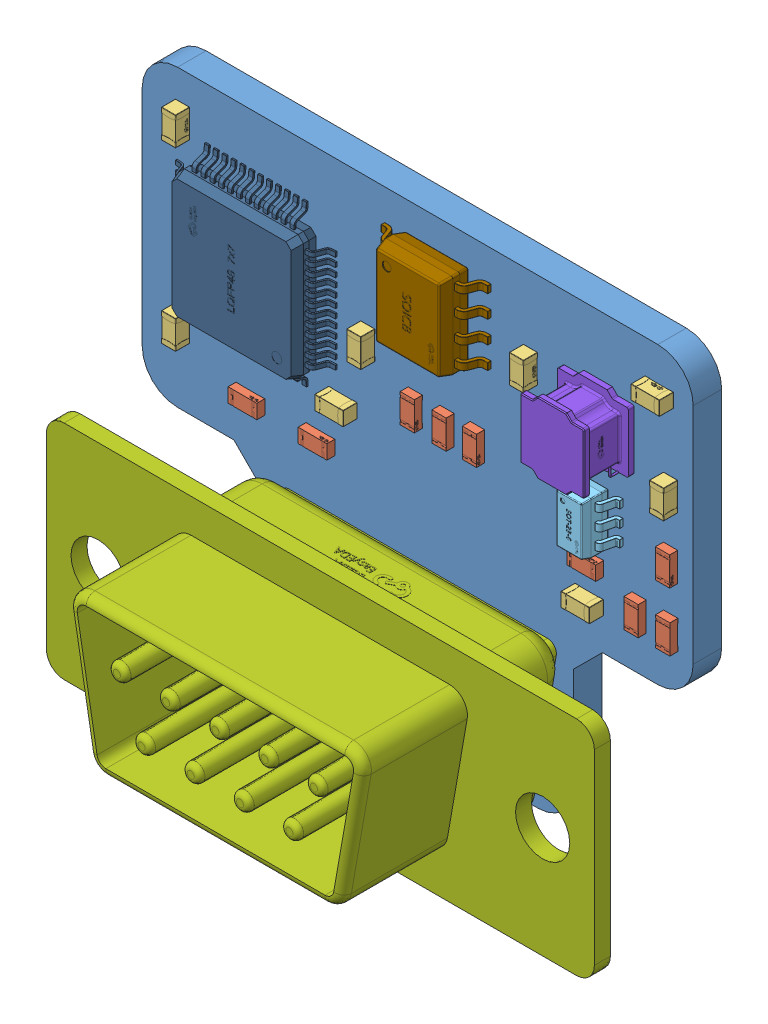
SolidWorks assembly ModbusRTU, configuration 默认. Lengths in mm.
Overall size (30.97 27.51 15.91).
109 component instances, 10 part files, 0 mates.
Components (placement in the parent):
- COMPOUND-1: COMPOUND [默认] at origin size (30.97 25.95 1.6)
- R4-1: R4 [默认] at (94.7422 -30.9881 1.6001) x (0 1 0) z (0 0 1) size (1.62 0.82 0.45)
  - R0603-1: R0603 [默认] at origin size (1.62 0.82 0.45)
    - COMPOUND_2-1: COMPOUND_2 [默认] at origin size (1.62 0.82 0.45)
- R5-1: R5 [默认] at (96.5202 -30.9881 1.6001) x (0 -1 0) z (0 0 1) size (1.62 0.82 0.45)
  - R0603-1: R0603 [默认] at origin size (1.62 0.82 0.45)
    - COMPOUND_2-1: COMPOUND_2 [默认] at origin size (1.62 0.82 0.45)
- R13-1: R13 [默认] at (97.0282 -34.0361 0) x (1 0 0) z (0 0 -1) size (1.62 0.82 0.45)
  - R0603-1: R0603 [默认] at origin size (1.62 0.82 0.45)
    - COMPOUND_2-1: COMPOUND_2 [默认] at origin size (1.62 0.82 0.45)
- R14-1: R14 [默认] at (93.9802 -36.8301 0) x (1 0 0) z (0 0 -1) size (1.62 0.82 0.45)
  - R0603-1: R0603 [默认] at origin size (1.62 0.82 0.45)
    - COMPOUND_2-1: COMPOUND_2 [默认] at origin size (1.62 0.82 0.45)
- R22-1: R22 [默认] at (93.9802 -34.0361 0) x (-1 0 0) z (0 0 -1) size (1.62 0.82 0.45)
  - R0603-1: R0603 [默认] at origin size (1.62 0.82 0.45)
    - COMPOUND_2-1: COMPOUND_2 [默认] at origin size (1.62 0.82 0.45)
- R23-1: R23 [默认] at (93.9802 -35.4331 0) x (1 0 0) z (0 0 -1) size (1.62 0.82 0.45)
  - R0603-1: R0603 [默认] at origin size (1.62 0.82 0.45)
    - COMPOUND_2-1: COMPOUND_2 [默认] at origin size (1.62 0.82 0.45)
- R24-1: R24 [默认] at (97.0282 -35.4331 0) x (-1 0 0) z (0 0 -1) size (1.62 0.82 0.45)
  - R0603-1: R0603 [默认] at origin size (1.62 0.82 0.45)
    - COMPOUND_2-1: COMPOUND_2 [默认] at origin size (1.62 0.82 0.45)
- R25-1: R25 [默认] at (97.0282 -36.8301 0) x (1 0 0) z (0 0 -1) size (1.62 0.82 0.45)
  - R0603-1: R0603 [默认] at origin size (1.62 0.82 0.45)
    - COMPOUND_2-1: COMPOUND_2 [默认] at origin size (1.62 0.82 0.45)
- R19-1: R19 [默认] at (85.1205 -23.622 0) x (1 0 0) z (0 0 -1) size (1.62 0.82 0.45)
  - R0603-1: R0603 [默认] at origin size (1.62 0.82 0.45)
    - COMPOUND_2-1: COMPOUND_2 [默认] at origin size (1.62 0.82 0.45)
- R20-1: R20 [默认] at (89.2812 -26.7971 0) x (1 0 0) z (0 0 -1) size (1.62 0.82 0.45)
  - R0603-1: R0603 [默认] at origin size (1.62 0.82 0.45)
    - COMPOUND_2-1: COMPOUND_2 [默认] at origin size (1.62 0.82 0.45)
- R21-1: R21 [默认] at (89.2812 -29.9721 0) x (1 0 0) z (0 0 -1) size (1.62 0.82 0.45)
  - R0603-1: R0603 [默认] at origin size (1.62 0.82 0.45)
    - COMPOUND_2-1: COMPOUND_2 [默认] at origin size (1.62 0.82 0.45)
- R26-1: R26 [默认] at (89.2812 -23.622 0) x (1 0 0) z (0 0 -1) size (1.62 0.82 0.45)
  - R0603-1: R0603 [默认] at origin size (1.62 0.82 0.45)
    - COMPOUND_2-1: COMPOUND_2 [默认] at origin size (1.62 0.82 0.45)
- R27-1: R27 [默认] at (89.2812 -33.1471 0) x (-1 0 0) z (0 0 -1) size (1.62 0.82 0.45)
  - R0603-1: R0603 [默认] at origin size (1.62 0.82 0.45)
    - COMPOUND_2-1: COMPOUND_2 [默认] at origin size (1.62 0.82 0.45)
- R29-1: R29 [默认] at (109.0932 -31.3691 1.6001) x (0 1 0) z (0 0 1) size (1.62 0.82 0.45)
  - R0603-1: R0603 [默认] at origin size (1.62 0.82 0.45)
    - COMPOUND_2-1: COMPOUND_2 [默认] at origin size (1.62 0.82 0.45)
- R30-1: R30 [默认] at (109.0932 -34.6711 1.6001) x (0 -1 0) z (0 0 1) size (1.62 0.82 0.45)
  - R0603-1: R0603 [默认] at origin size (1.62 0.82 0.45)
    - COMPOUND_2-1: COMPOUND_2 [默认] at origin size (1.62 0.82 0.45)
- R31-1: R31 [默认] at (107.3152 -34.6711 1.6001) x (0 -1 0) z (0 0 1) size (1.62 0.82 0.45)
  - R0603-1: R0603 [默认] at origin size (1.62 0.82 0.45)
    - COMPOUND_2-1: COMPOUND_2 [默认] at origin size (1.62 0.82 0.45)
- R28-1: R28 [默认] at (104.5212 -33.5281 1.6001) x (-1 0 0) z (0 0 1) size (1.62 0.82 0.45)
  - R0603-1: R0603 [默认] at origin size (1.62 0.82 0.45)
    - COMPOUND_2-1: COMPOUND_2 [默认] at origin size (1.62 0.82 0.45)
- R11-1: R11 [默认] at (89.4082 -35.1791 1.6001) x (-1 0 0) z (0 0 1) size (1.62 0.82 0.45)
  - R0603-1: R0603 [默认] at origin size (1.62 0.82 0.45)
    - COMPOUND_2-1: COMPOUND_2 [默认] at origin size (1.62 0.82 0.45)
- R12-1: R12 [默认] at (85.4712 -35.1791 1.6001) x (-1 0 0) z (0 0 1) size (1.62 0.82 0.45)
  - R0603-1: R0603 [默认] at origin size (1.62 0.82 0.45)
    - COMPOUND_2-1: COMPOUND_2 [默认] at origin size (1.62 0.82 0.45)
- R3-1: R3 [默认] at (98.2347 -30.9246 1.6001) x (0 1 0) z (0 0 1) size (1.62 0.82 0.45)
  - R0603-1: R0603 [默认] at origin size (1.62 0.82 0.45)
    - COMPOUND_2-1: COMPOUND_2 [默认] at origin size (1.62 0.82 0.45)
- C24-1: C24 [默认] at (85.1128 -26.0942 0) x (-1 0 0) z (0 0 -1) size (1.6 0.84 0.84)
  - C0603-1: C0603 [默认] at origin size (1.6 0.84 0.84)
    - SOLID-1: SOLID [默认] at origin size (1.6 0.84 0.84)
- C5-1: C5 [默认] at (90.6782 -32.7661 1.6001) x (-1 0 0) z (0 0 1) size (1.6 0.84 0.84)
  - C0603-1: C0603 [默认] at origin size (1.6 0.84 0.84)
    - SOLID-1: SOLID [默认] at origin size (1.6 0.84 0.84)
- C6-1: C6 [默认] at (81.6612 -33.4011 1.6001) x (0 1 0) z (0 0 1) size (1.6 0.84 0.84)
  - C0603-1: C0603 [默认] at origin size (1.6 0.84 0.84)
    - SOLID-1: SOLID [默认] at origin size (1.6 0.84 0.84)
- C7-1: C7 [默认] at (81.6612 -23.495 1.6001) x (0 -1 0) z (0 0 1) size (1.6 0.84 0.84)
  - C0603-1: C0603 [默认] at origin size (1.6 0.84 0.84)
    - SOLID-1: SOLID [默认] at origin size (1.6 0.84 0.84)
- C8-1: C8 [默认] at (92.0752 -29.0831 1.6001) x (0 1 0) z (0 0 1) size (1.6 0.84 0.84)
  - C0603-1: C0603 [默认] at origin size (1.6 0.84 0.84)
    - SOLID-1: SOLID [默认] at origin size (1.6 0.84 0.84)
- C28-1: C28 [默认] at (104.5212 -35.4331 1.6001) x (-1 0 0) z (0 0 1) size (1.6 0.84 0.84)
  - C0603-1: C0603 [默认] at origin size (1.6 0.84 0.84)
    - SOLID-1: SOLID [默认] at origin size (1.6 0.84 0.84)
- C29-1: C29 [默认] at (108.4582 -23.368 1.6001) size (1.6 0.84 0.84)
  - C0603-1: C0603 [默认] at origin size (1.6 0.84 0.84)
    - SOLID-1: SOLID [默认] at origin size (1.6 0.84 0.84)
- C30-1: C30 [默认] at (109.0932 -27.9401 1.6001) x (0 1 0) z (0 0 1) size (1.6 0.84 0.84)
  - C0603-1: C0603 [默认] at origin size (1.6 0.84 0.84)
    - SOLID-1: SOLID [默认] at origin size (1.6 0.84 0.84)
- C3-1: C3 [默认] at (101.2192 -25.6541 1.6001) x (0 -1 0) z (0 0 1) size (1.6 0.84 0.84)
  - C0603-1: C0603 [默认] at origin size (1.6 0.84 0.84)
    - SOLID-1: SOLID [默认] at origin size (1.6 0.84 0.84)
- U8-1: U8 [默认] at (85.1203 -29.9292 0) x (0 1 0) z (0 0 -1) size (3 3.01 0.81)
  - SENSOR-SMD_L3.0-W3.0-P1.00-BR-1: SENSOR-SMD_L3.0-W3.0-P1.00-BR [默认] at origin size (3 3.01 0.81)
    - SOLID_2-1: SOLID_2 [默认] at origin size (3 3.01 0.81)
- U11-1: U11 [默认] at (105.0292 -30.7341 1.6001) x (-1 0 0) z (0 0 1) size (2.82 2.9 1.66)
  - SOT-23-6_L2.9-W1.6-P0.95-LS2.8-BR-1: SOT-23-6_L2.9-W1.6-P0.95-LS2.8-BR [默认] at origin size (2.82 2.9 1.66)
    - COMPOUND_3-1: COMPOUND_3 [默认] at origin size (2.82 2.9 1.66)
- U9-1: U9 [默认] at (85.1255 -34.0361 0) x (0 -1 0) z (0 0 -1) size (2 2 0.81)
  - HLGA-10L_LPS22HBTR-1: HLGA-10L_LPS22HBTR [默认] at origin size (2 2 0.81)
    - COMPOUND_4-1: COMPOUND_4 [默认] at origin size (2 2 0.81)
- CN1-1: CN1 [默认] at (94.9025 -42.3543 1.6001) size (30.81 12.5 15.91)
  - DSUB-SMD_9P_DMS-9P-1: DSUB-SMD_9P_DMS-9P [默认] at origin size (30.81 12.5 15.91)
    - SOLID_3-1: SOLID_3 [默认] at origin size (30.81 12.5 15.91)
- L1-1: L1 [默认] at (105.0292 -26.4161 1.6001) size (4 4 2.61)
  - IND-SMD_L4.0-W4.0_FNR40XXS-1: IND-SMD_L4.0-W4.0_FNR40XXS [默认] at origin size (4 4 2.61)
    - SOLID_4-1: SOLID_4 [默认] at origin size (4 4 2.61)
- U10-1: U10 [默认] at (96.0122 -24.892 1.6001) x (0 -1 0) z (0 0 1) size (4.81 6 1.73)
  - SOIC-8_L5.0-W4.0-P1.27-LS6.0-BL-1: SOIC-8_L5.0-W4.0-P1.27-LS6.0-BL [默认] at origin size (4.81 6 1.73)
    - COMPOUND_5-1: COMPOUND_5 [默认] at origin size (4.81 6 1.73)
- U2-1: U2 [默认] at (85.8522 -28.4481 1.6001) x (0 1 0) z (0 0 1) size (9 9 1.46)
  - LQFP-48_L7.0-W7.0-P0.50-LS9.0-BL-1: LQFP-48_L7.0-W7.0-P0.50-LS9.0-BL [默认] at origin size (9 9 1.46)
    - COMPOUND_6-1: COMPOUND_6 [默认] at origin size (9 9 1.46)
